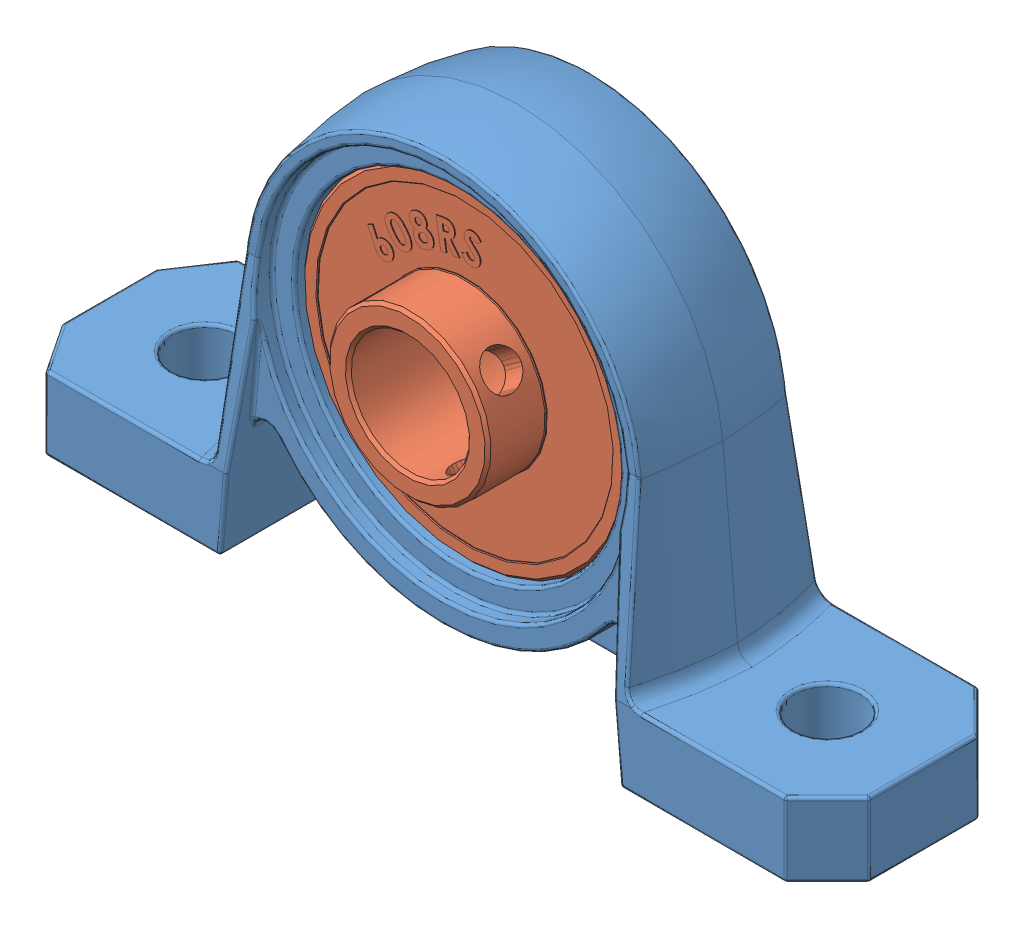
SolidWorks assembly KP08, configuration Default. Lengths in mm.
Overall size (55 40.88 13.92).
2 component instances, 2 part files, 4 mates.
Components (placement in the parent):
- KP08-2: KP08 [По умолчанию] at (2.2899 16 0) size (55 40.88 13.13)
- 608RS-2: 608RS [Default] at (2.2899 16 -3.5) x (0.16403 0.986455 0) z (0 0 1) size (22 22 10.85)
Mates (geometry in assembly coordinates):
- Концентричный2: concentric aligned: cylinder of KP08-2 through (2.2899 16 5) axis (0 0 -1) radius 11; cylinder of 608RS-2 through (2.2899 16 3.5) axis (0 0 -1) radius 11
- Расстояние1: distance = 0.5 mm aligned: plane of 608RS-2 through (2.2899 16 -3.5) normal (0 0 -1); plane of KP08-2 through (2.2899 16 -4) normal (0 0 -1)
- Совпадение2: coincident aligned: circle of KP08-2; plane of assembly through (0 0 0) normal (0 0 1)
- Совпадение3: coincident anti-aligned: plane of KP08-2 through (2.2899 0 6.5) normal (0 -1 0); plane of assembly through (0 0 0) normal (0 1 0)
